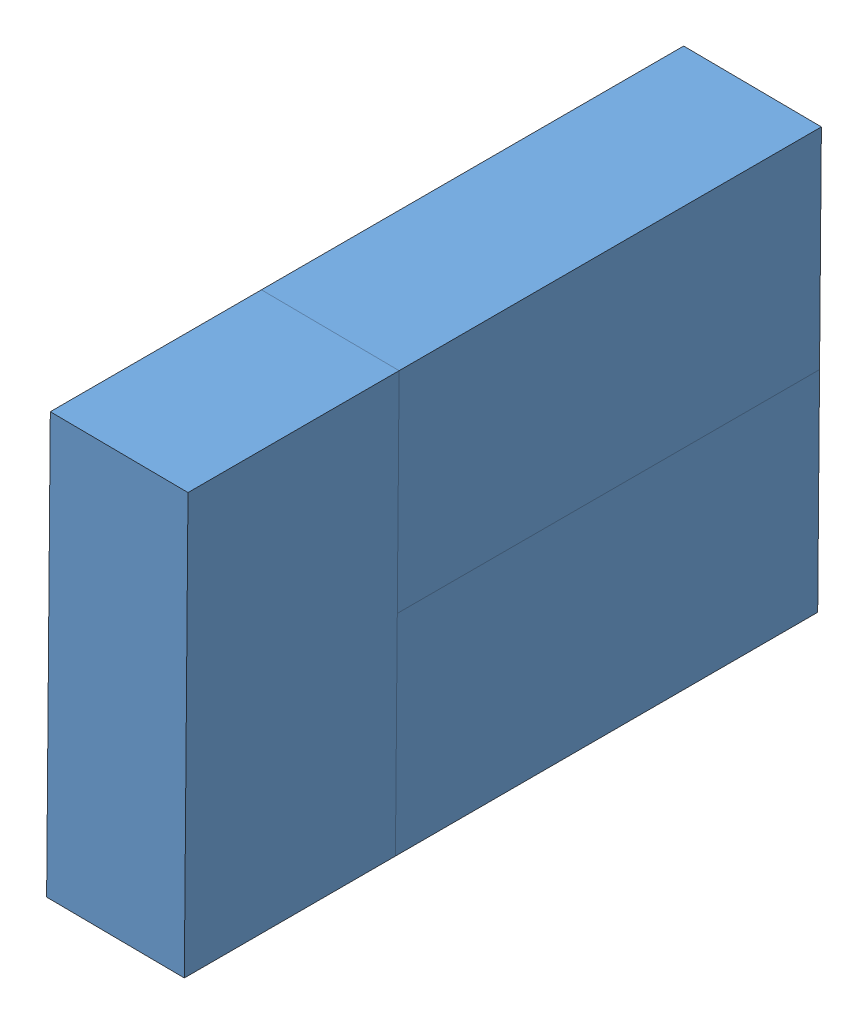
SolidWorks assembly Assem1, configuration Default. Lengths in mm.
Overall size (77 230.65 345).
3 component instances, 1 part files, 4 mates.
Components (placement in the parent):
- Brick-Whole-1: Brick-Whole [Default] x (-0.008727 -0.999962 0) z (0 0 1) size (230 75 115)
- Brick-Whole-2: Brick-Whole [Default] at (0.5018 57.4978 -172.5) x (0 0 1) z (0.008727 0.999962 0) size (230 75 115)
- Brick-Whole-3: Brick-Whole [Default] at (-0.5018 -57.4978 -172.5) x (0 0 1) z (0.008727 0.999962 0) size (230 75 115)
Mates (geometry in assembly coordinates):
- Coincident1: coincident anti-aligned: line of Brick-Whole-1 through (36.495 -115.3229 -57.5) axis (0.008727 0.999962 0); line of Brick-Whole-3 through (37.4986 -0.3272 -57.5) axis (-0.008727 -0.999962 0)
- Coincident2: coincident aligned: line of Brick-Whole-1 through (36.495 -115.3229 -57.5) axis (-0.999962 0.008727 0); line of Brick-Whole-3 through (36.495 -115.3229 -57.5) axis (-0.999962 0.008727 0)
- Coincident5: coincident: line of Brick-Whole-1 through (38.5021 114.6684 -57.5) axis (-0.999962 0.008727 0); line of Brick-Whole-2 through (38.5021 114.6684 -57.5) axis (-0.999962 0.008727 0)
- Coincident6: coincident anti-aligned: line of Brick-Whole-2 through (37.4986 -0.3272 -57.5) axis (0 0 -1); line of Brick-Whole-3 through (37.4986 -0.3272 -287.5) axis (0 0 1)
